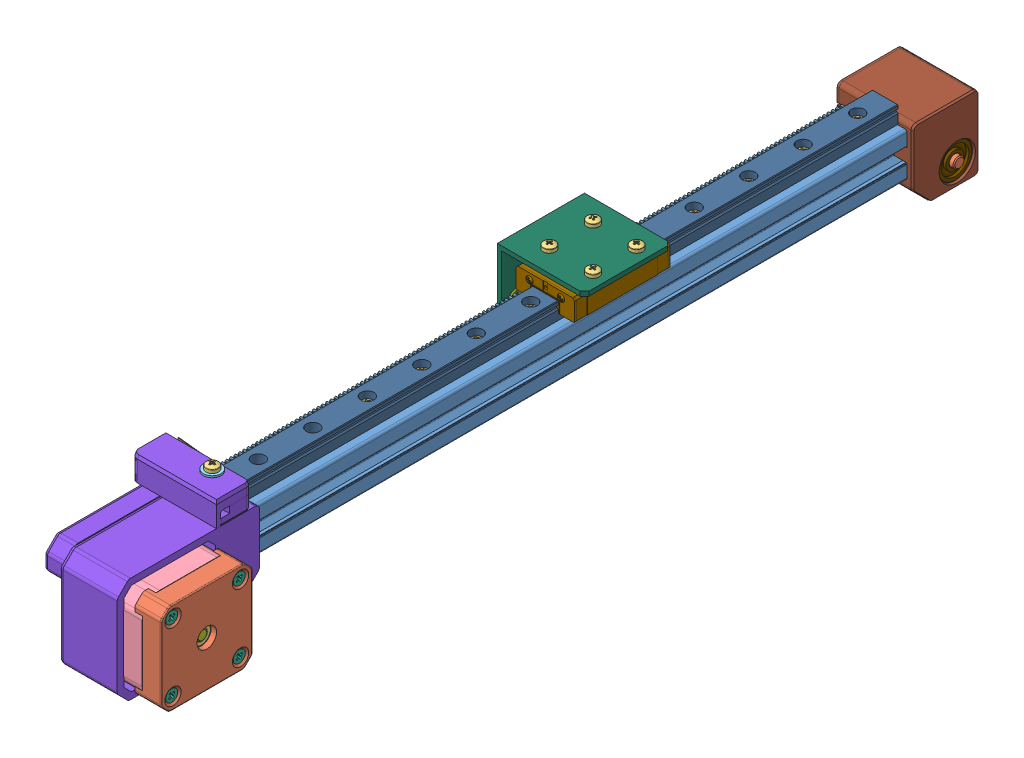
SolidWorks assembly Assem1, configuration По умолчанию. Lengths in mm.
Overall size (72 62.65 440.81).
71 component instances, 24 part files, 140 mates.
Components (placement in the parent):
- rsi_2020_274-1: rsi_2020_274 [По умолчанию] at origin size (20 20 324)
- 17HM15-0904S-1: 17HM15-0904S [По умолчанию] at (30 -11.15 353.15) x (0 0 -1) z (0 1 0) size (42.3 62 42.3)
  - nema17_bottom_40mm-1: nema17_bottom_40mm [По умолчанию] at origin size (42 12 42)
  - radial ball bearing_68_din-1: radial ball bearing_68_din [DIN 625 - 625 - 8,SI,NC,8_68] at (0 5 0) x (0 -1 0) z (0 0 1) size (5 16 16)
  - nema17_middle_40mm-1: nema17_middle_40mm [По умолчанию] at (0 8.5 0) size (42.3 23.5 42.3)
  - nema17_top_40mm-1: nema17_top_40mm [По умолчанию] at (0 32 0) size (42.3 12.6 42.3)
  - radial ball bearing_68_din-3: radial ball bearing_68_din [DIN 625 - 625 - 8,SI,NC,8_68] at (0 38.1 0) x (0 1 0) z (0 0 1) size (5 16 16)
  - countersunk flat head cross recess screw_din-1: countersunk flat head cross recess screw_din [ISO 7046-1 - M3 x 30 - Z --- 30N] at (15.5 0.6 15.5) x (0 1 0) z (0.546944 0 -0.837169) size (30 5.5 5.5)
  - countersunk flat head cross recess screw_din-2: countersunk flat head cross recess screw_din [ISO 7046-1 - M3 x 25 - Z --- 25N] at (15.5 0.6 -15.5) x (0 1 0) z (0.546944 0 -0.837169) size (25 5.5 5.5)
  - countersunk flat head cross recess screw_din-3: countersunk flat head cross recess screw_din [ISO 7046-1 - M3 x 30 - Z --- 30N] at (-15.5 0.6 15.5) x (0 1 0) z (0.546944 0 -0.837169) size (30 5.5 5.5)
  - countersunk flat head cross recess screw_din-4: countersunk flat head cross recess screw_din [ISO 7046-1 - M3 x 30 - Z --- 30N] at (-15.5 0.6 -15.5) x (0 1 0) z (0.546944 0 -0.837169) size (30 5.5 5.5)
  - nema17_shaft_40mm-1: nema17_shaft_40mm [По умолчанию] at (0 2 0) x (-0.412738 0 0.91085) z (-0.91085 0 -0.412738) size (5 60 5)
- nema17_mount_1-1: nema17_mount_1 [По умолчанию] at (-13 -10.7443 344.7873) x (0 0 -1) z (1 0 0) size (65.25 59.3 39.22)
- MGN12-H-1: MGN12-H [По умолчанию] at (0 18 145.9667) size (27 10 45.19)
- MGN12_250-1: MGN12_250 [По умолчанию] at (0 14 12) size (12 8 300)
- idle_pul_mount_1-1: idle_pul_mount_1 [По умолчанию] at (13 -3.403 -4.0666) x (0 0 1) z (-1 0 0) size (30 34 35)
- GT2_16T_13x14-1: GT2_16T_13x14 [Конфигурация1] at (-26.5 -11.15 353.15) x (1 0 0) z (0 0.386253 0.922393) size (14.1 13 13)
- GT2_16T_13x14-2: GT2_16T_13x14 [Конфигурация1] at (-26.5 -11.15 -8.1562) x (1 0 0) z (0 0.133178 -0.991092) size (14.1 13 13)
- SS-5GL_microswitch-2: SS-5GL_microswitch [Default] at (-42.2883 22.25 325.1397) x (0 -1 0) z (1 0 0) size (6.5 17.14 19.7)
- belt_250-1: belt_250 [По умолчанию] at (-19.83 -1.6143 147.7424) size (6 22.23 372.5)
- alum_40x40x2-1: alum_40x40x2 [По умолчанию] at (-21.9 23 165.9667) x (0 0 -1) z (0 -1 0) size (40 40 40)
- idle_pulley_16-1: idle_pulley_16 [По умолчанию] at (-16.4162 -0.75 133.4667) x (0 1 0) z (0 0 1) size (13 9 13)
- idle_pulley_16-2: idle_pulley_16 [По умолчанию] at (-16.4162 -0.75 158.4667) x (0 1 0) z (0 0 1) size (13 9 13)
- mgn12_fix-1: mgn12_fix [По умолчанию] at (0 12.9786 54.5) x (1 0 0) z (0 1 0) size (9.5 35 6)
- mgn12_fix-2: mgn12_fix [По умолчанию] at (0 12.9786 104.5) x (1 0 0) z (0 1 0) size (9.5 35 6)
- mgn12_fix-3: mgn12_fix [По умолчанию] at (0 12.9786 254.5) x (1 0 0) z (0 1 0) size (9.5 35 6)
- mgn12_fix-4: mgn12_fix [По умолчанию] at (0 12.9786 154.5) x (1 0 0) z (0 1 0) size (9.5 35 6)
- mgn12_fix-5: mgn12_fix [По умолчанию] at (0 12.9786 204.5) x (1 0 0) z (0 1 0) size (9.5 35 6)
- instrument ball bearing_68_am-1: instrument ball bearing_68_am [AFBMA 12.1.4.1 - 0050-16 - 8,SI,NC,8_68] at (-9.5 -11.15 -8.1562) size (5 16 16)
- instrument ball bearing_68_am-2: instrument ball bearing_68_am [AFBMA 12.1.4.1 - 0050-16 - 8,SI,NC,8_68] at (9.5 -11.15 -8.1562) size (5 16 16)
- socket head cap screw_am-1: socket head cap screw_am [B18.3.1M - 5 x 0.8 x 20 Hex SHCS -- 20NHX] at (0 0 330.85) x (0 0 -1) z (1 0 0) size (25 8.5 8.5)
- socket head cap screw_am-2: socket head cap screw_am [B18.3.1M - 5 x 0.8 x 20 Hex SHCS -- 20NHX] at (0 0 -11) x (0 0 1) z (-1 0 0) size (25 8.5 8.5)
- continous stud_am-1: continous stud_am [AM -- M5 x 45  N] at (-31 -11.15 -8.1562) size (45 5 5)
- pan head cross recess screw_din-1: pan head cross recess screw_din [ISO 7045 - M3 x 16 - Z --- 16N] at (-10 -0.75 158.4667) x (-1 0 0) z (0 0.924225 0.381849) size (18.35 5.6 5.6)
- pan head cross recess screw_din-2: pan head cross recess screw_din [ISO 7045 - M3 x 16 - Z --- 16N] at (-10 -0.75 133.4667) x (-1 0 0) z (0 0.924225 0.381849) size (18.35 5.6 5.6)
- prevailing torque nut style 1 insert_din-3: prevailing torque nut style 1 insert_din [DIN EN ISO 7040 - M3 - N] at (-26.05 -0.75 133.4667) x (0 0 1) z (-1 0 0) size (5.5 6.35 4.5)
- prevailing torque nut style 1 insert_din-4: prevailing torque nut style 1 insert_din [DIN EN ISO 7040 - M3 - N] at (-26.05 -0.75 158.4667) x (0 0 1) z (-1 0 0) size (5.5 6.35 4.5)
- plain washer 6902 type abc_din-1: plain washer 6902 type abc_din [DIN 6902-A3.2] at (-13 -26.65 368.65) x (-1 0 0) z (0 0.924225 0.381849) size (0.8 8 8)
- pan head cross recess screw_din-4: pan head cross recess screw_din [ISO 7045 - M3 x 6 - Z --- 6N] at (-16.2 -26.65 368.65) size (8.35 5.6 5.6)
- pan head cross recess screw_din-5: pan head cross recess screw_din [ISO 7045 - M3 x 6 - Z --- 6N] at (-16.2 -26.65 337.65) size (8.35 5.6 5.6)
- plain washer 6902 type abc_din-2: plain washer 6902 type abc_din [DIN 6902-A3.2] at (-13 -26.65 337.65) x (-1 0 0) z (0 0.924225 0.381849) size (0.8 8 8)
- pan head cross recess screw_din-6: pan head cross recess screw_din [ISO 7045 - M3 x 16 - Z --- 16N] at (-25.2 4.35 337.65) size (18.35 5.6 5.6)
- plain washer 6902 type abc_din-3: plain washer 6902 type abc_din [DIN 6902-A3.2] at (-22 4.35 337.65) x (-1 0 0) z (0 0.924225 0.381849) size (0.8 8 8)
- plain washer 6902 type abc_din-4: plain washer 6902 type abc_din [DIN 6902-A3.2] at (-22 4.35 368.65) x (-1 0 0) z (0 0.924225 0.381849) size (0.8 8 8)
- pan head cross recess screw_din-7: pan head cross recess screw_din [ISO 7045 - M3 x 20 - Z --- 20N] at (-25.2 4.35 368.65) size (22.35 5.6 5.6)
- pan head cross recess screw_din-9: pan head cross recess screw_din [ISO 7045 - M3 x 8 - Z --- 8N] at (0 15.9 24.5) x (0 -1 0) z (0 0 1) size (10.35 5.6 5.6)
- pan head cross recess screw_din-10: pan head cross recess screw_din [ISO 7045 - M3 x 8 - Z --- 8N] at (0 15.9 49.5) x (0 -1 0) z (-0.931961 0 -0.362559) size (10.35 5.6 5.6)
- hex nut style 1 gradeab_din-1: hex nut style 1 gradeab_din [Hexagon Nut ISO 4032 - M3 - D - N] at (0 5.1 24.5) x (0.5 0 0.866025) z (0 -1 0) size (5.5 6.35 2.4)
- hex nut style 1 gradeab_din-2: hex nut style 1 gradeab_din [Hexagon Nut ISO 4032 - M3 - D - N] at (0 5.1 49.5) x (0.5 0 0.866025) z (0 -1 0) size (5.5 6.35 2.4)
- hex nut style 1 gradeab_din-3: hex nut style 1 gradeab_din [Hexagon Nut ISO 4032 - M3 - D - N] at (0 5.1 99.5) x (0.5 0 0.866025) z (0 -1 0) size (5.5 6.35 2.4)
- hex nut style 1 gradeab_din-4: hex nut style 1 gradeab_din [Hexagon Nut ISO 4032 - M3 - D - N] at (0 5.1 74.5) x (0.5 0 0.866025) z (0 -1 0) size (5.5 6.35 2.4)
- pan head cross recess screw_din-11: pan head cross recess screw_din [ISO 7045 - M3 x 8 - Z --- 8N] at (0 15.9 74.5) x (0 -1 0) z (0 0 1) size (10.35 5.6 5.6)
- pan head cross recess screw_din-12: pan head cross recess screw_din [ISO 7045 - M3 x 8 - Z --- 8N] at (0 15.9 99.5) x (0 -1 0) z (-0.931961 0 -0.362559) size (10.35 5.6 5.6)
- hex nut style 1 gradeab_din-5: hex nut style 1 gradeab_din [Hexagon Nut ISO 4032 - M3 - D - N] at (0 5.1 249.5) x (0.5 0 0.866025) z (0 -1 0) size (5.5 6.35 2.4)
- hex nut style 1 gradeab_din-6: hex nut style 1 gradeab_din [Hexagon Nut ISO 4032 - M3 - D - N] at (0 5.1 224.5) x (0.5 0 0.866025) z (0 -1 0) size (5.5 6.35 2.4)
- pan head cross recess screw_din-13: pan head cross recess screw_din [ISO 7045 - M3 x 8 - Z --- 8N] at (0 15.9 224.5) x (0 -1 0) z (0 0 1) size (10.35 5.6 5.6)
- pan head cross recess screw_din-14: pan head cross recess screw_din [ISO 7045 - M3 x 8 - Z --- 8N] at (0 15.9 249.5) x (0 -1 0) z (-0.931961 0 -0.362559) size (10.35 5.6 5.6)
- hex nut style 1 gradeab_din-7: hex nut style 1 gradeab_din [Hexagon Nut ISO 4032 - M3 - D - N] at (0 5.1 149.5) x (0.5 0 0.866025) z (0 -1 0) size (5.5 6.35 2.4)
- hex nut style 1 gradeab_din-8: hex nut style 1 gradeab_din [Hexagon Nut ISO 4032 - M3 - D - N] at (0 5.1 124.5) x (0.5 0 0.866025) z (0 -1 0) size (5.5 6.35 2.4)
- pan head cross recess screw_din-15: pan head cross recess screw_din [ISO 7045 - M3 x 8 - Z --- 8N] at (0 15.9 124.5) x (0 -1 0) z (0 0 1) size (10.35 5.6 5.6)
- pan head cross recess screw_din-16: pan head cross recess screw_din [ISO 7045 - M3 x 8 - Z --- 8N] at (0 15.9 149.5) x (0 -1 0) z (-0.931961 0 -0.362559) size (10.35 5.6 5.6)
- hex nut style 1 gradeab_din-9: hex nut style 1 gradeab_din [Hexagon Nut ISO 4032 - M3 - D - N] at (0 5.1 199.5) x (0.5 0 0.866025) z (0 -1 0) size (5.5 6.35 2.4)
- hex nut style 1 gradeab_din-10: hex nut style 1 gradeab_din [Hexagon Nut ISO 4032 - M3 - D - N] at (0 5.1 174.5) x (0.5 0 0.866025) z (0 -1 0) size (5.5 6.35 2.4)
- pan head cross recess screw_din-17: pan head cross recess screw_din [ISO 7045 - M3 x 8 - Z --- 8N] at (0 15.9 174.5) x (0 -1 0) z (0 0 1) size (10.35 5.6 5.6)
- pan head cross recess screw_din-18: pan head cross recess screw_din [ISO 7045 - M3 x 8 - Z --- 8N] at (0 15.9 199.5) x (0 -1 0) z (-0.931961 0 -0.362559) size (10.35 5.6 5.6)
- pan head cross recess screw_din-19: pan head cross recess screw_din [ISO 7045 - M3 x 6 - Z --- 6N] at (-10 27.4 155.9667) x (0 -1 0) z (0 0 1) size (8.35 5.6 5.6)
- pan head cross recess screw_din-20: pan head cross recess screw_din [ISO 7045 - M3 x 6 - Z --- 6N] at (-10 27.4 135.9667) x (0 -1 0) z (-0.54801 0 0.836471) size (8.35 5.6 5.6)
- pan head cross recess screw_din-21: pan head cross recess screw_din [ISO 7045 - M3 x 6 - Z --- 6N] at (10 27.4 135.9667) x (0 -1 0) z (0 0 1) size (8.35 5.6 5.6)
- pan head cross recess screw_din-22: pan head cross recess screw_din [ISO 7045 - M3 x 6 - Z --- 6N] at (10 27.4 155.9667) x (0 -1 0) z (-0.158888 0 0.987297) size (8.35 5.6 5.6)
- plain washer 6902 type abc_din-5: plain washer 6902 type abc_din [DIN 6902-A3.2] at (0 24 320.6521) x (0 1 0) z (0.924225 0 0.381849) size (0.8 8 8)
- pan head cross recess screw_din-23: pan head cross recess screw_din [ISO 7045 - M3 x 16 - Z --- 16N] at (0 27.2 320.6521) x (0 -1 0) z (0 0 1) size (18.35 5.6 5.6)
Mates (geometry in assembly coordinates):
- Concentric1: concentric aligned: cylinder of rsi_2020_274-1 through (0 0 324) axis (0 0 -1) radius 2.5; cylinder of nema17_mount_1-1 through (0 0 377.251) axis (0 0 -1) radius 3.1
- Coincident4: coincident anti-aligned: plane of rsi_2020_274-1 through (0 0 324) normal (0 0 1); plane of nema17_mount_1-1 through (-13 -10.7443 324) normal (0 0 -1)
- Parallel2: parallel aligned: plane of rsi_2020_274-1 through (10 0 324) normal (1 0 0); plane of nema17_mount_1-1 through (13 -10.7443 344.7873) normal (1 0 0)
- Concentric2: concentric anti-aligned: cylinder of 17HM15-0904S-1/nema17_top_40mm-1 through (-12 -11.15 353.15) axis (1 0 0) radius 11; cylinder of nema17_mount_1-1 through (-10 -11.15 353.15) axis (-1 0 0) radius 11.05
- Coincident6: coincident anti-aligned: plane of 17HM15-0904S-1/nema17_top_40mm-1 through (-10 -11.15 353.15) normal (-1 0 0); plane of nema17_mount_1-1 through (-10 -10.7443 344.7873) normal (1 0 0)
- Parallel3: parallel aligned: plane of 17HM15-0904S-1/nema17_middle_40mm-1 through (-2 10 367.5735) normal (0 1 0); plane of nema17_mount_1-1 through (13 13 344.7873) normal (0 1 0)
- Coincident8: coincident anti-aligned: plane of MGN12-H-1 through (6 18 162.1667) normal (-1 0 0); plane of MGN12_250-1 through (6 10.3 312) normal (1 0 0)
- Coincident9: coincident anti-aligned: plane of MGN12-H-1 through (0 18 162.1667) normal (0 -1 0); plane of MGN12_250-1 through (-5.7 18 312) normal (0 1 0)
- Coincident10: coincident anti-aligned: plane of rsi_2020_274-1 through (0 10 324) normal (0 1 0); plane of MGN12_250-1 through (-5.7 10 312) normal (0 -1 0)
- Coincident11: coincident anti-aligned: plane of nema17_mount_1-1 through (13 -10.7443 312) normal (0 0 -1); plane of MGN12_250-1 through (6.3091 15.5 312) normal (0 0 1)
- Distance2: distance = 4 mm aligned: plane of MGN12_250-1 through (-6 10.3 312) normal (-1 0 0); plane of rsi_2020_274-1 through (-10 0 324) normal (-1 0 0)
- Concentric5: concentric anti-aligned: cylinder of rsi_2020_274-1 through (0 0 324) axis (0 0 -1) radius 2.5; cylinder of idle_pul_mount_1-1 through (0 0 -18.001) axis (0 0 1) radius 3.1
- Coincident14: coincident anti-aligned: plane of rsi_2020_274-1 through (0 0 0) normal (0 0 -1); plane of idle_pul_mount_1-1 through (13 -3.403 0) normal (0 0 1)
- Concentric6: concentric aligned: cylinder of 17HM15-0904S-1/nema17_shaft_40mm-1 through (-32 -11.15 353.15) axis (1 0 0) radius 2.5; cylinder of GT2_16T_13x14-1 through (-26.5 -11.15 353.15) axis (1 0 0) radius 2.5
- Coincident15: coincident anti-aligned: plane of idle_pul_mount_1-1 through (-7 -11.15 -8.1562) normal (-1 0 0); plane of instrument ball bearing_68_am-1 through (-7 -3.45 -8.1562) normal (1 0 0)
- Concentric7: concentric anti-aligned: cylinder of idle_pul_mount_1-1 through (-7 -11.15 -8.1562) axis (-1 0 0) radius 8; cylinder of instrument ball bearing_68_am-1 through (-30.1375 -11.15 -8.1562) axis (1 0 0) radius 8
- Coincident16: coincident aligned: circle of idle_pul_mount_1-1; plane of instrument ball bearing_68_am-2 through (7 -4.8 -8.1562) normal (-1 0 0)
- Concentric8: concentric aligned: cylinder of idle_pul_mount_1-1 through (7 -11.15 -8.1562) axis (1 0 0) radius 8; cylinder of instrument ball bearing_68_am-2 through (-11.1375 -11.15 -8.1562) axis (1 0 0) radius 8
- Concentric9: concentric anti-aligned: cylinder of idle_pul_mount_1-1 through (0 0 -18.001) axis (0 0 1) radius 3.1; cylinder of socket head cap screw_am-2 through (0 0 -42.75) axis (0 0 -1) radius 4.25
- Coincident17: coincident anti-aligned: plane of idle_pul_mount_1-1 through (0 0 -6) normal (0 0 -1); plane of socket head cap screw_am-2 through (0 4.25 -6) normal (0 0 1)
- Concentric10: concentric anti-aligned: cylinder of nema17_mount_1-1 through (0 0 377.251) axis (0 0 -1) radius 3.1; cylinder of socket head cap screw_am-1 through (0 0 362.6) axis (0 0 1) radius 2.5
- Coincident18: coincident anti-aligned: plane of nema17_mount_1-1 through (0 0 325.85) normal (0 0 1); plane of socket head cap screw_am-1 through (0 4.25 325.85) normal (0 0 -1)
- Concentric11: concentric anti-aligned: cylinder of instrument ball bearing_68_am-1 through (-30.1375 -11.15 -8.1562) axis (1 0 0) radius 2.5; cylinder of continous stud_am-1 through (-34.175 -11.15 -8.1562) axis (-1 0 0) radius 2.5
- Distance3: distance = 2 mm aligned: plane of continous stud_am-1 through (14 -8.65 -8.1562) normal (1 0 0); plane of instrument ball bearing_68_am-2 through (12 -8.35 -8.1562) normal (1 0 0)
- Concentric12: concentric anti-aligned: cylinder of continous stud_am-1 through (-34.175 -11.15 -8.1562) axis (-1 0 0) radius 2.5; cylinder of GT2_16T_13x14-2 through (-26.5 -11.15 -8.1562) axis (1 0 0) radius 2.5
- Coincident20: coincident aligned: plane of nema17_mount_1-1 through (13 13 344.7873) normal (0 1 0); plane of idle_pul_mount_1-1 through (-13 13 -4.0666) normal (0 1 0)
- Coincident21: coincident aligned: plane of GT2_16T_13x14-1 through (-26.5 -11.15 353.15) normal (-1 0 0); plane of GT2_16T_13x14-2 through (-26.5 -11.15 -8.1562) normal (-1 0 0)
- Distance4: distance = 0.5 mm anti-aligned: plane of GT2_16T_13x14-2 through (-20.33 -11.15 -8.1562) normal (1 0 0); plane of belt_250-1 through (-19.83 -16.385 108.7112) normal (-1 0 0)
- Coincident23: coincident anti-aligned: plane of MGN12-H-1 through (0 23 162.1667) normal (0 1 0); plane of alum_40x40x2-1 through (-21.9 23 125.9667) normal (0 -1 0)
- Concentric13: concentric anti-aligned: cylinder of alum_40x40x2-1 through (16.101 -0.75 133.4667) axis (-1 0 0) radius 1.5; cylinder of idle_pulley_16-1 through (-16.4162 -0.75 133.4667) axis (1 0 0) radius 1.5
- Concentric14: concentric anti-aligned: cylinder of alum_40x40x2-1 through (16.101 -0.75 158.4667) axis (-1 0 0) radius 1.5; cylinder of idle_pulley_16-2 through (-16.4162 -0.75 158.4667) axis (1 0 0) radius 1.5
- Distance6: distance = 0.5 mm anti-aligned: plane of idle_pulley_16-1 through (-21.4 -0.75 131.9667) normal (-1 0 0); plane of alum_40x40x2-1 through (-21.9 -15 125.9667) normal (1 0 0)
- Distance7: distance = 0.5 mm anti-aligned: plane of idle_pulley_16-2 through (-21.4 -0.75 156.9667) normal (-1 0 0); plane of alum_40x40x2-1 through (-21.9 -15 125.9667) normal (1 0 0)
- Concentric15: concentric aligned: cylinder of idle_pulley_16-2 through (-16.4162 -0.75 158.4667) axis (1 0 0) radius 1.5; cylinder of pan head cross recess screw_din-1 through (15.4 -0.75 158.4667) axis (1 0 0) radius 2.8
- Coincident28: coincident anti-aligned: plane of idle_pulley_16-2 through (-12.4 -0.75 151.9667) normal (1 0 0); plane of pan head cross recess screw_din-1 through (-12.4 -1.3228 159.853) normal (-1 0 0)
- Concentric16: concentric aligned: cylinder of idle_pulley_16-1 through (-16.4162 -0.75 133.4667) axis (1 0 0) radius 1.5; cylinder of pan head cross recess screw_din-2 through (15.4 -0.75 133.4667) axis (1 0 0) radius 2.8
- Coincident29: coincident anti-aligned: plane of idle_pulley_16-1 through (-12.4 -0.75 126.9667) normal (1 0 0); plane of pan head cross recess screw_din-2 through (-12.4 -1.3228 134.853) normal (-1 0 0)
- Concentric20: concentric aligned: cylinder of MGN12-H-1 through (-10 17.15 155.9667) axis (0 1 0) radius 1.5; cylinder of alum_40x40x2-1 through (-10 -15.001 155.9667) axis (0 1 0) radius 1.5
- Concentric21: concentric aligned: cylinder of MGN12-H-1 through (10 17.15 135.9667) axis (0 1 0) radius 1.5; cylinder of alum_40x40x2-1 through (10 -15.001 135.9667) axis (0 1 0) radius 1.5
- Concentric29: concentric anti-aligned: cylinder of pan head cross recess screw_din-2 through (15.4 -0.75 133.4667) axis (1 0 0) radius 1.5; cylinder of prevailing torque nut style 1 insert_din-3 through (-23.9 -0.75 133.4667) axis (-1 0 0) radius 1.25
- Concentric30: concentric anti-aligned: cylinder of pan head cross recess screw_din-1 through (15.4 -0.75 158.4667) axis (1 0 0) radius 1.5; cylinder of prevailing torque nut style 1 insert_din-4 through (-23.9 -0.75 158.4667) axis (-1 0 0) radius 1.25
- Coincident36: coincident anti-aligned: plane of alum_40x40x2-1 through (-23.9 25 125.9667) normal (-1 0 0); plane of prevailing torque nut style 1 insert_din-3 through (-23.9 -0.75 127.9667) normal (1 0 0)
- Coincident37: coincident anti-aligned: plane of alum_40x40x2-1 through (-23.9 25 125.9667) normal (-1 0 0); plane of prevailing torque nut style 1 insert_din-4 through (-23.9 -0.75 152.9667) normal (1 0 0)
- Concentric32: concentric anti-aligned: cylinder of nema17_mount_1-1 through (-10 -26.65 368.65) axis (-1 0 0) radius 1.6; cylinder of plain washer 6902 type abc_din-1 through (-13.8 -26.65 368.65) axis (1 0 0) radius 1.6
- Coincident39: coincident anti-aligned: plane of nema17_mount_1-1 through (-13 -10.7443 344.7873) normal (-1 0 0); plane of plain washer 6902 type abc_din-1 through (-13 -26.65 368.65) normal (1 0 0)
- Coincident40: coincident anti-aligned: plane of plain washer 6902 type abc_din-1 through (-13.8 -26.65 368.65) normal (-1 0 0); plane of pan head cross recess screw_din-4 through (-13.8 -25.15 368.65) normal (1 0 0)
- Concentric41: concentric anti-aligned: cylinder of plain washer 6902 type abc_din-1 through (-13.8 -26.65 368.65) axis (1 0 0) radius 1.6; cylinder of pan head cross recess screw_din-4 through (-41.6 -26.65 368.65) axis (-1 0 0) radius 1.5
- Coincident47: coincident anti-aligned: plane of pan head cross recess screw_din-5 through (-13.8 -25.15 337.65) normal (1 0 0); plane of plain washer 6902 type abc_din-2 through (-13.8 -26.65 337.65) normal (-1 0 0)
- Concentric42: concentric anti-aligned: cylinder of pan head cross recess screw_din-5 through (-41.6 -26.65 337.65) axis (-1 0 0) radius 1.5; cylinder of plain washer 6902 type abc_din-2 through (-13.8 -26.65 337.65) axis (1 0 0) radius 1.6
- Concentric43: concentric anti-aligned: cylinder of nema17_mount_1-1 through (-10 -26.65 337.65) axis (-1 0 0) radius 1.6; cylinder of plain washer 6902 type abc_din-2 through (-13.8 -26.65 337.65) axis (1 0 0) radius 1.6
- Coincident48: coincident anti-aligned: plane of nema17_mount_1-1 through (-13 -10.7443 344.7873) normal (-1 0 0); plane of plain washer 6902 type abc_din-2 through (-13 -26.65 337.65) normal (1 0 0)
- Coincident49: coincident anti-aligned: plane of pan head cross recess screw_din-6 through (-22.8 5.85 337.65) normal (1 0 0); plane of plain washer 6902 type abc_din-3 through (-22.8 4.35 337.65) normal (-1 0 0)
- Concentric44: concentric anti-aligned: cylinder of pan head cross recess screw_din-6 through (-50.6 4.35 337.65) axis (-1 0 0) radius 1.5; cylinder of plain washer 6902 type abc_din-3 through (-22.8 4.35 337.65) axis (1 0 0) radius 1.6
- Concentric45: concentric anti-aligned: cylinder of nema17_mount_1-1 through (-10 4.35 337.65) axis (-1 0 0) radius 1.6; cylinder of plain washer 6902 type abc_din-3 through (-22.8 4.35 337.65) axis (1 0 0) radius 1.6
- Coincident50: coincident anti-aligned: plane of nema17_mount_1-1 through (-22 2 314) normal (-1 0 0); plane of plain washer 6902 type abc_din-3 through (-22 4.35 337.65) normal (1 0 0)
- Coincident51: coincident anti-aligned: plane of plain washer 6902 type abc_din-4 through (-22.8 4.35 368.65) normal (-1 0 0); plane of pan head cross recess screw_din-7 through (-22.8 5.85 368.65) normal (1 0 0)
- Concentric46: concentric anti-aligned: cylinder of plain washer 6902 type abc_din-4 through (-22.8 4.35 368.65) axis (1 0 0) radius 1.6; cylinder of pan head cross recess screw_din-7 through (-50.6 4.35 368.65) axis (-1 0 0) radius 1.5
- Concentric47: concentric anti-aligned: cylinder of nema17_mount_1-1 through (-10 4.35 368.65) axis (-1 0 0) radius 1.6; cylinder of plain washer 6902 type abc_din-4 through (-22.8 4.35 368.65) axis (1 0 0) radius 1.6
- Coincident52: coincident anti-aligned: plane of nema17_mount_1-1 through (-22 2 314) normal (-1 0 0); plane of plain washer 6902 type abc_din-4 through (-22 4.35 368.65) normal (1 0 0)
- Distance9: distance = 5.5 mm aligned: plane of GT2_16T_13x14-1 through (-26.5 -11.15 353.15) normal (-1 0 0); plane of 17HM15-0904S-1/nema17_shaft_40mm-1 through (-32 -11.15 353.15) normal (-1 0 0)
- Concentric50: concentric anti-aligned: cylinder of MGN12_250-1 through (0 10 24.5) axis (0 1 0) radius 1.75; cylinder of mgn12_fix-1 through (0 10.001 24.5) axis (0 -1 0) radius 1.6
- Concentric51: concentric anti-aligned: cylinder of MGN12_250-1 through (0 10 49.5) axis (0 1 0) radius 1.75; cylinder of mgn12_fix-1 through (0 10.001 49.5) axis (0 -1 0) radius 1.6
- Coincident55: coincident anti-aligned: plane of MGN12_250-1 through (-5.7 10 312) normal (0 -1 0); plane of mgn12_fix-1 through (-3 10 19.5) normal (0 1 0)
- Concentric54: concentric aligned: cylinder of MGN12_250-1 through (0 10 49.5) axis (0 1 0) radius 1.75; cylinder of pan head cross recess screw_din-10 through (0 41.3 49.5) axis (0 1 0) radius 2.8
- Coincident57: coincident anti-aligned: plane of MGN12_250-1 through (0 13.5 49.5) normal (0 1 0); plane of pan head cross recess screw_din-10 through (-0.5438 13.5 50.8979) normal (0 -1 0)
- Parallel6: parallel aligned: plane of mgn12_fix-1 through (-2.9 7.5 22.8257) normal (0.5 0 0.866025); plane of hex nut style 1 gradeab_din-1 through (0 7.5 27.6754) normal (0.5 0 0.866025)
- Coincident61: coincident anti-aligned: plane of mgn12_fix-1 through (0 7.5 54.5) normal (0 -1 0); plane of hex nut style 1 gradeab_din-1 through (-2.75 7.5 26.0877) normal (0 1 0)
- Concentric57: concentric anti-aligned: cylinder of pan head cross recess screw_din-10 through (0 41.3 49.5) axis (0 1 0) radius 1.5; cylinder of hex nut style 1 gradeab_din-2 through (0 7.5 49.5) axis (0 -1 0) radius 1.25
- Parallel7: parallel aligned: plane of mgn12_fix-1 through (0 7.5 46.1514) normal (0.5 0 0.866025); plane of hex nut style 1 gradeab_din-2 through (0 7.5 52.6754) normal (0.5 0 0.866025)
- Coincident62: coincident anti-aligned: plane of mgn12_fix-1 through (0 7.5 54.5) normal (0 -1 0); plane of hex nut style 1 gradeab_din-2 through (-2.75 7.5 51.0877) normal (0 1 0)
- Concentric59: concentric aligned: cylinder of MGN12_250-1 through (0 10 24.5) axis (0 1 0) radius 1.75; cylinder of pan head cross recess screw_din-9 through (0 41.3 24.5) axis (0 1 0) radius 1.5
- Coincident64: coincident anti-aligned: plane of MGN12_250-1 through (0 13.5 24.5) normal (0 1 0); plane of pan head cross recess screw_din-9 through (1.5 13.5 24.5) normal (0 -1 0)
- Concentric85: concentric anti-aligned: cylinder of pan head cross recess screw_din-9 through (0 41.3 24.5) axis (0 1 0) radius 1.5; cylinder of hex nut style 1 gradeab_din-1 through (0 7.5 24.5) axis (0 -1 0) radius 1.25
- Parallel16: parallel aligned: plane of mgn12_fix-2 through (-2.9 7.5 72.8257) normal (0.5 0 0.866025); plane of hex nut style 1 gradeab_din-4 through (0 7.5 77.6754) normal (0.5 0 0.866025)
- Coincident85: coincident anti-aligned: plane of mgn12_fix-2 through (0 7.5 104.5) normal (0 -1 0); plane of hex nut style 1 gradeab_din-4 through (-2.75 7.5 76.0877) normal (0 1 0)
- Concentric86: concentric anti-aligned: cylinder of hex nut style 1 gradeab_din-3 through (0 7.5 99.5) axis (0 -1 0) radius 1.25; cylinder of pan head cross recess screw_din-12 through (0 41.3 99.5) axis (0 1 0) radius 1.5
- Parallel17: parallel aligned: plane of mgn12_fix-2 through (0 7.5 96.1514) normal (0.5 0 0.866025); plane of hex nut style 1 gradeab_din-3 through (0 7.5 102.6754) normal (0.5 0 0.866025)
- Coincident86: coincident anti-aligned: plane of mgn12_fix-2 through (0 7.5 104.5) normal (0 -1 0); plane of hex nut style 1 gradeab_din-3 through (-2.75 7.5 101.0877) normal (0 1 0)
- Concentric87: concentric anti-aligned: cylinder of hex nut style 1 gradeab_din-4 through (0 7.5 74.5) axis (0 -1 0) radius 1.25; cylinder of pan head cross recess screw_din-11 through (0 41.3 74.5) axis (0 1 0) radius 1.5
- Concentric88: concentric anti-aligned: cylinder of MGN12_250-1 through (0 10 74.5) axis (0 1 0) radius 1.75; cylinder of mgn12_fix-2 through (0 10.001 74.5) axis (0 -1 0) radius 1.6
- Concentric89: concentric anti-aligned: cylinder of MGN12_250-1 through (0 10 99.5) axis (0 1 0) radius 1.75; cylinder of mgn12_fix-2 through (0 10.001 99.5) axis (0 -1 0) radius 1.6
- Coincident87: coincident anti-aligned: plane of MGN12_250-1 through (-5.7 10 312) normal (0 -1 0); plane of mgn12_fix-2 through (-3 10 69.5) normal (0 1 0)
- Concentric90: concentric aligned: cylinder of MGN12_250-1 through (0 10 99.5) axis (0 1 0) radius 1.75; cylinder of pan head cross recess screw_din-12 through (0 41.3 99.5) axis (0 1 0) radius 2.8
- Coincident88: coincident anti-aligned: plane of MGN12_250-1 through (0 13.5 49.5) normal (0 1 0); plane of pan head cross recess screw_din-12 through (-0.5438 13.5 100.8979) normal (0 -1 0)
- Concentric91: concentric aligned: cylinder of MGN12_250-1 through (0 10 74.5) axis (0 1 0) radius 1.75; cylinder of pan head cross recess screw_din-11 through (0 41.3 74.5) axis (0 1 0) radius 1.5
- Coincident89: coincident anti-aligned: plane of MGN12_250-1 through (0 13.5 24.5) normal (0 1 0); plane of pan head cross recess screw_din-11 through (1.5 13.5 74.5) normal (0 -1 0)
- Parallel18: parallel aligned: plane of mgn12_fix-3 through (-2.9 7.5 222.8257) normal (0.5 0 0.866025); plane of hex nut style 1 gradeab_din-6 through (0 7.5 227.6754) normal (0.5 0 0.866025)
- Coincident90: coincident anti-aligned: plane of mgn12_fix-3 through (0 7.5 254.5) normal (0 -1 0); plane of hex nut style 1 gradeab_din-6 through (-2.75 7.5 226.0877) normal (0 1 0)
- Concentric92: concentric anti-aligned: cylinder of hex nut style 1 gradeab_din-5 through (0 7.5 249.5) axis (0 -1 0) radius 1.25; cylinder of pan head cross recess screw_din-14 through (0 41.3 249.5) axis (0 1 0) radius 1.5
- Parallel19: parallel aligned: plane of mgn12_fix-3 through (0 7.5 246.1514) normal (0.5 0 0.866025); plane of hex nut style 1 gradeab_din-5 through (0 7.5 252.6754) normal (0.5 0 0.866025)
- Coincident91: coincident anti-aligned: plane of mgn12_fix-3 through (0 7.5 254.5) normal (0 -1 0); plane of hex nut style 1 gradeab_din-5 through (-2.75 7.5 251.0877) normal (0 1 0)
- Concentric93: concentric anti-aligned: cylinder of hex nut style 1 gradeab_din-6 through (0 7.5 224.5) axis (0 -1 0) radius 1.25; cylinder of pan head cross recess screw_din-13 through (0 41.3 224.5) axis (0 1 0) radius 1.5
- Concentric94: concentric anti-aligned: cylinder of MGN12_250-1 through (0 10 224.5) axis (0 1 0) radius 1.75; cylinder of mgn12_fix-3 through (0 10.001 224.5) axis (0 -1 0) radius 1.6
- Coincident92: coincident anti-aligned: plane of MGN12_250-1 through (-5.7 10 312) normal (0 -1 0); plane of mgn12_fix-3 through (-3 10 219.5) normal (0 1 0)
- Coincident93: coincident anti-aligned: plane of MGN12_250-1 through (0 13.5 49.5) normal (0 1 0); plane of pan head cross recess screw_din-14 through (-0.5438 13.5 250.8979) normal (0 -1 0)
- Coincident94: coincident anti-aligned: plane of MGN12_250-1 through (0 13.5 24.5) normal (0 1 0); plane of pan head cross recess screw_din-13 through (1.5 13.5 224.5) normal (0 -1 0)
- Concentric95: concentric anti-aligned: cylinder of MGN12_250-1 through (0 10 249.5) axis (0 1 0) radius 1.75; cylinder of mgn12_fix-3 through (0 10.001 249.5) axis (0 -1 0) radius 1.6
- Concentric96: concentric aligned: cylinder of MGN12_250-1 through (0 10 249.5) axis (0 1 0) radius 1.75; cylinder of pan head cross recess screw_din-14 through (0 41.3 249.5) axis (0 1 0) radius 2.8
- Concentric97: concentric aligned: cylinder of MGN12_250-1 through (0 10 224.5) axis (0 1 0) radius 1.75; cylinder of pan head cross recess screw_din-13 through (0 41.3 224.5) axis (0 1 0) radius 1.5
- Parallel20: parallel aligned: plane of mgn12_fix-4 through (-2.9 7.5 122.8257) normal (0.5 0 0.866025); plane of hex nut style 1 gradeab_din-8 through (0 7.5 127.6754) normal (0.5 0 0.866025)
- Coincident95: coincident anti-aligned: plane of mgn12_fix-4 through (0 7.5 154.5) normal (0 -1 0); plane of hex nut style 1 gradeab_din-8 through (-2.75 7.5 126.0877) normal (0 1 0)
- Concentric98: concentric anti-aligned: cylinder of hex nut style 1 gradeab_din-7 through (0 7.5 149.5) axis (0 -1 0) radius 1.25; cylinder of pan head cross recess screw_din-16 through (0 41.3 149.5) axis (0 1 0) radius 1.5
- Parallel21: parallel aligned: plane of mgn12_fix-4 through (0 7.5 146.1514) normal (0.5 0 0.866025); plane of hex nut style 1 gradeab_din-7 through (0 7.5 152.6754) normal (0.5 0 0.866025)
- Coincident96: coincident anti-aligned: plane of mgn12_fix-4 through (0 7.5 154.5) normal (0 -1 0); plane of hex nut style 1 gradeab_din-7 through (-2.75 7.5 151.0877) normal (0 1 0)
- Concentric99: concentric anti-aligned: cylinder of hex nut style 1 gradeab_din-8 through (0 7.5 124.5) axis (0 -1 0) radius 1.25; cylinder of pan head cross recess screw_din-15 through (0 41.3 124.5) axis (0 1 0) radius 1.5
- Concentric100: concentric anti-aligned: cylinder of MGN12_250-1 through (0 10 124.5) axis (0 1 0) radius 1.75; cylinder of mgn12_fix-4 through (0 10.001 124.5) axis (0 -1 0) radius 1.6
- Coincident97: coincident anti-aligned: plane of MGN12_250-1 through (-5.7 10 312) normal (0 -1 0); plane of mgn12_fix-4 through (-3 10 119.5) normal (0 1 0)
- Coincident98: coincident anti-aligned: plane of MGN12_250-1 through (0 13.5 49.5) normal (0 1 0); plane of pan head cross recess screw_din-16 through (-0.5438 13.5 150.8979) normal (0 -1 0)
- Coincident99: coincident anti-aligned: plane of MGN12_250-1 through (0 13.5 24.5) normal (0 1 0); plane of pan head cross recess screw_din-15 through (1.5 13.5 124.5) normal (0 -1 0)
- Concentric101: concentric anti-aligned: cylinder of MGN12_250-1 through (0 10 149.5) axis (0 1 0) radius 1.75; cylinder of mgn12_fix-4 through (0 10.001 149.5) axis (0 -1 0) radius 1.6
- Concentric102: concentric aligned: cylinder of MGN12_250-1 through (0 10 149.5) axis (0 1 0) radius 1.75; cylinder of pan head cross recess screw_din-16 through (0 41.3 149.5) axis (0 1 0) radius 2.8
- Concentric103: concentric aligned: cylinder of MGN12_250-1 through (0 10 124.5) axis (0 1 0) radius 1.75; cylinder of pan head cross recess screw_din-15 through (0 41.3 124.5) axis (0 1 0) radius 1.5
- Parallel22: parallel aligned: plane of mgn12_fix-5 through (-2.9 7.5 172.8257) normal (0.5 0 0.866025); plane of hex nut style 1 gradeab_din-10 through (0 7.5 177.6754) normal (0.5 0 0.866025)
- Coincident100: coincident anti-aligned: plane of mgn12_fix-5 through (0 7.5 204.5) normal (0 -1 0); plane of hex nut style 1 gradeab_din-10 through (-2.75 7.5 176.0877) normal (0 1 0)
- Concentric104: concentric anti-aligned: cylinder of hex nut style 1 gradeab_din-9 through (0 7.5 199.5) axis (0 -1 0) radius 1.25; cylinder of pan head cross recess screw_din-18 through (0 41.3 199.5) axis (0 1 0) radius 1.5
- Parallel23: parallel aligned: plane of mgn12_fix-5 through (0 7.5 196.1514) normal (0.5 0 0.866025); plane of hex nut style 1 gradeab_din-9 through (0 7.5 202.6754) normal (0.5 0 0.866025)
- Coincident101: coincident anti-aligned: plane of mgn12_fix-5 through (0 7.5 204.5) normal (0 -1 0); plane of hex nut style 1 gradeab_din-9 through (-2.75 7.5 201.0877) normal (0 1 0)
- Concentric105: concentric anti-aligned: cylinder of hex nut style 1 gradeab_din-10 through (0 7.5 174.5) axis (0 -1 0) radius 1.25; cylinder of pan head cross recess screw_din-17 through (0 41.3 174.5) axis (0 1 0) radius 1.5
- Concentric106: concentric anti-aligned: cylinder of MGN12_250-1 through (0 10 174.5) axis (0 1 0) radius 1.75; cylinder of mgn12_fix-5 through (0 10.001 174.5) axis (0 -1 0) radius 1.6
- Coincident102: coincident anti-aligned: plane of MGN12_250-1 through (-5.7 10 312) normal (0 -1 0); plane of mgn12_fix-5 through (-3 10 169.5) normal (0 1 0)
- Coincident103: coincident anti-aligned: plane of MGN12_250-1 through (0 13.5 49.5) normal (0 1 0); plane of pan head cross recess screw_din-18 through (-0.5438 13.5 200.8979) normal (0 -1 0)
- Coincident104: coincident anti-aligned: plane of MGN12_250-1 through (0 13.5 24.5) normal (0 1 0); plane of pan head cross recess screw_din-17 through (1.5 13.5 174.5) normal (0 -1 0)
- Concentric107: concentric anti-aligned: cylinder of MGN12_250-1 through (0 10 199.5) axis (0 1 0) radius 1.75; cylinder of mgn12_fix-5 through (0 10.001 199.5) axis (0 -1 0) radius 1.6
- Concentric108: concentric aligned: cylinder of MGN12_250-1 through (0 10 199.5) axis (0 1 0) radius 1.75; cylinder of pan head cross recess screw_din-18 through (0 41.3 199.5) axis (0 1 0) radius 2.8
- Concentric109: concentric aligned: cylinder of MGN12_250-1 through (0 10 174.5) axis (0 1 0) radius 1.75; cylinder of pan head cross recess screw_din-17 through (0 41.3 174.5) axis (0 1 0) radius 1.5
- Concentric110: concentric aligned: cylinder of alum_40x40x2-1 through (-10 -15.001 155.9667) axis (0 1 0) radius 1.5; cylinder of pan head cross recess screw_din-19 through (-10 52.8 155.9667) axis (0 1 0) radius 2.8
- Coincident105: coincident anti-aligned: plane of alum_40x40x2-1 through (16.1 25 125.9667) normal (0 1 0); plane of pan head cross recess screw_din-19 through (-8.5 25 155.9667) normal (0 -1 0)
- Concentric111: concentric aligned: cylinder of alum_40x40x2-1 through (-10 -15.001 135.9667) axis (0 1 0) radius 1.5; cylinder of pan head cross recess screw_din-20 through (-10 52.8 135.9667) axis (0 1 0) radius 2.8
- Coincident106: coincident anti-aligned: plane of alum_40x40x2-1 through (16.1 25 125.9667) normal (0 1 0); plane of pan head cross recess screw_din-20 through (-8.7453 25 136.7887) normal (0 -1 0)
- Concentric112: concentric aligned: cylinder of alum_40x40x2-1 through (10 -15.001 135.9667) axis (0 1 0) radius 1.5; cylinder of pan head cross recess screw_din-21 through (10 52.8 135.9667) axis (0 1 0) radius 2.8
- Coincident107: coincident anti-aligned: plane of alum_40x40x2-1 through (16.1 25 125.9667) normal (0 1 0); plane of pan head cross recess screw_din-21 through (11.5 25 135.9667) normal (0 -1 0)
- Concentric113: concentric aligned: cylinder of alum_40x40x2-1 through (10 -15.001 155.9667) axis (0 1 0) radius 1.5; cylinder of pan head cross recess screw_din-22 through (10 52.8 155.9667) axis (0 1 0) radius 2.8
- Coincident108: coincident anti-aligned: plane of alum_40x40x2-1 through (16.1 25 125.9667) normal (0 1 0); plane of pan head cross recess screw_din-22 through (11.4809 25 156.205) normal (0 -1 0)
- Concentric118: concentric aligned: cylinder of nema17_mount_1-1 through (-9.5152 15.6 322.6147) axis (0 1 0) radius 1.275; cylinder of SS-5GL_microswitch-2 through (-9.5152 15.75 322.6147) axis (0 1 0) radius 1.275
- Concentric119: concentric aligned: cylinder of nema17_mount_1-1 through (-19.2152 15.6 322.6147) axis (0 1 0) radius 1.275; cylinder of SS-5GL_microswitch-2 through (-19.2152 15.75 322.6147) axis (0 1 0) radius 1.275
- Coincident113: coincident anti-aligned: plane of nema17_mount_1-1 through (-13 16 344.7873) normal (0 1 0); plane of SS-5GL_microswitch-2 through (-42.2883 16 325.1397) normal (0 -1 0)
- Coincident114: coincident anti-aligned: plane of plain washer 6902 type abc_din-5 through (0 24.8 320.6521) normal (0 1 0); plane of pan head cross recess screw_din-23 through (1.5 24.8 320.6521) normal (0 -1 0)
- Concentric120: concentric anti-aligned: cylinder of plain washer 6902 type abc_din-5 through (0 24.8 320.6521) axis (0 -1 0) radius 1.6; cylinder of pan head cross recess screw_din-23 through (0 52.6 320.6521) axis (0 1 0) radius 1.5
- Concentric121: concentric anti-aligned: cylinder of nema17_mount_1-1 through (0 3 320.6521) axis (0 1 0) radius 1.6; cylinder of plain washer 6902 type abc_din-5 through (0 24.8 320.6521) axis (0 -1 0) radius 1.6
- Coincident115: coincident anti-aligned: plane of nema17_mount_1-1 through (10.8 24 317.9147) normal (0 1 0); plane of plain washer 6902 type abc_din-5 through (0 24 320.6521) normal (0 -1 0)
